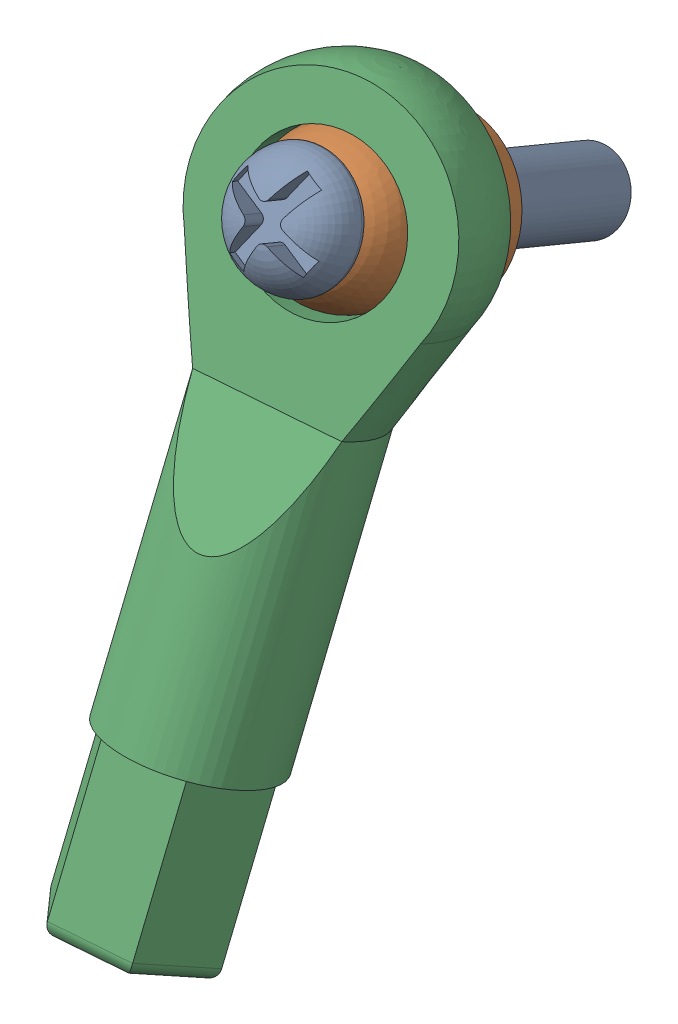
SolidWorks assembly Ball joint rod end assembly (rear radius arm), configuration Default. Lengths in mm.
Overall size (11.62 32.61 25.57).
3 component instances, 3 part files, 4 mates.
Components (placement in the parent):
- ball joint bolt-1: ball joint bolt [Default] at (611.0253 931.8996 1263.1195) x (-0.895336 0.43401 -0.100039) z (0.431219 0.788491 -0.438557) size (4.76 18.12 4.76)
- Ball joint-1: Ball joint [Default] at (612.0284 935.8218 1271.1576) x (0.844037 -0.515914 0.146405) z (-0.524575 -0.737506 0.42533) size (6.5 7 6.5)
- Rod End-1: Rod End [Default] at (612.0323 915.3521 1283.6981) x (0.981079 -0.087398 -0.172761) z (-0.020735 -0.934613 0.355061) size (10 6.2 29)
Mates (geometry in assembly coordinates):
- Concentric5: concentric anti-aligned: cylinder of ball joint bolt-1 through (611.0253 931.8996 1263.1195) axis (-0.111459 -0.435795 -0.893118) radius 1.5; cylinder of Ball joint-1 through (612.0284 935.8218 1271.1576) axis (0.111459 0.435795 0.893118) radius 1.5
- Coincident26: coincident anti-aligned: plane of ball joint bolt-1 through (614.3754 938.1128 1277.5845) normal (-0.111459 -0.435795 -0.893118); plane of Ball joint-1 through (611.4089 939.7279 1277.1666) normal (0.111459 0.435795 0.893118)
- Concentric6: concentric: sphere of Ball joint-1; cylinder of Rod End-1 through (612.2412 937.2657 1273.7985) axis (0.192496 0.344761 0.918741) radius 3
- Coincident29: coincident: point of Ball joint-1; point of Rod End-1
